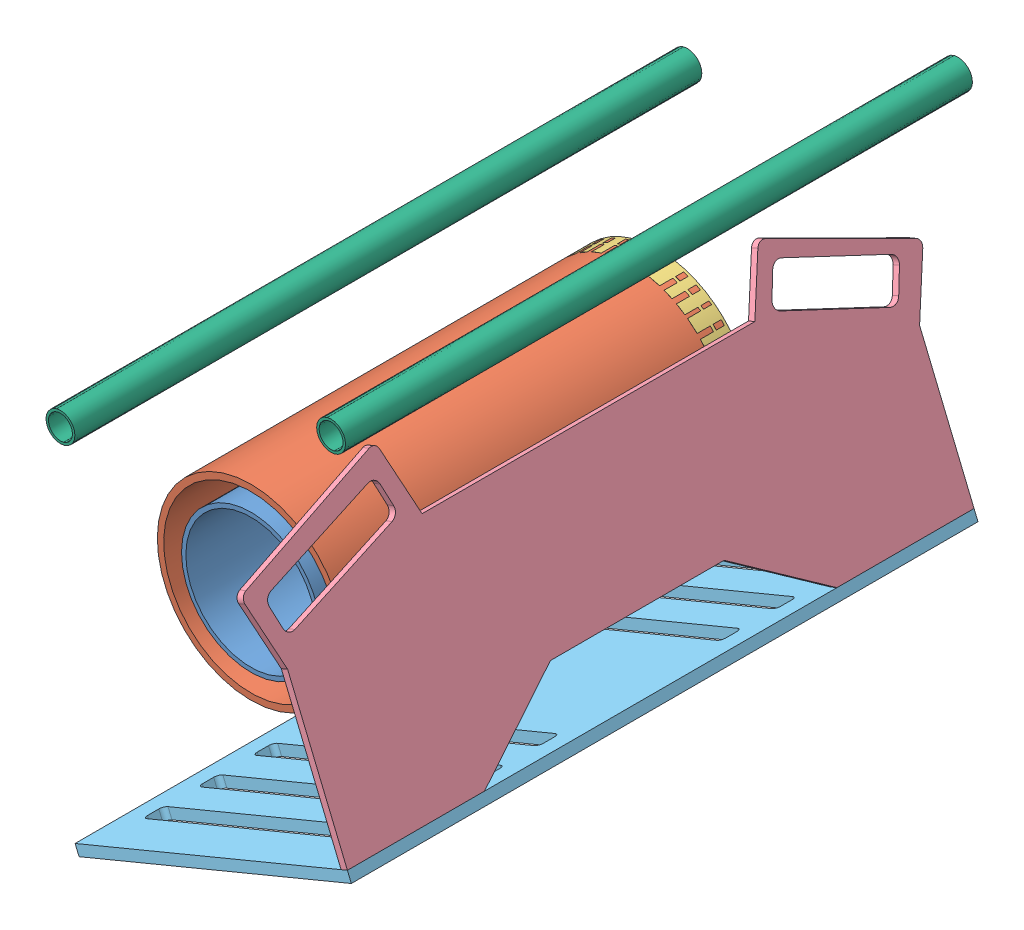
SolidWorks assembly Assem1, configuration Default. Lengths in mm.
Overall size (597.25 584.72 1095.77).
7 component instances, 6 part files, 11 mates.
Components (placement in the parent):
- inner_main_shell-1: inner_main_shell [Default] at (214.1698 315.1095 156.1721) size (202.6 202.6 590)
- outer_main_shell-1: outer_main_shell [Default] at (214.1698 315.1095 451.1721) x (0.580771 -0.814067 0) z (0 0 1) size (273.14 273.14 590)
- cap-1: cap [Default] at (214.1698 315.1095 155.0269) x (-0.923728 -0.383049 0) z (0 0 -1) size (273.04 273.04 38.74)
- side_frame-1: side_frame [Default] at (436.2247 330.1201 441.0447) x (0 0 -1) z (0.923728 0.383049 0) size (976.99 396.41 10)
- flat_frame-1: flat_frame [Default] at (313.8941 89.9427 441.0447) x (0 0 1) z (-0.923728 -0.383049 0) size (914 15 430)
- Pontoon-1: Pontoon [48925K94] at (-63.6755 384.8539 288.9721) size (42.16 42.16 914.4)
- Pontoon-2: Pontoon [48925K94] at (331.0443 571.2275 288.9721) size (42.16 42.16 914.4)
Mates (geometry in assembly coordinates):
- Concentric1: concentric anti-aligned: cylinder of inner_main_shell-1 through (214.1698 315.1095 746.1721) axis (0 0 -1) radius 95; cylinder of outer_main_shell-1 through (214.1698 315.1095 515.1017) axis (0 0 1) radius 127.3
- Coincident1: coincident aligned: plane of inner_main_shell-1 through (214.1698 315.1095 746.1721) normal (0 0 1); plane of outer_main_shell-1 through (325.3469 394.4254 746.1721) normal (0 0 1)
- Concentric2: concentric aligned: cylinder of inner_main_shell-1 through (214.1698 315.1095 746.1721) axis (0 0 -1) radius 95; cylinder of cap-1 through (214.1698 315.1095 101.1915) axis (0 0 -1) radius 95
- Coincident3: coincident anti-aligned: plane of outer_main_shell-1 through (325.3469 394.4254 156.1721) normal (0 0 -1); plane of cap-1 through (163.0251 438.4456 156.1721) normal (0 0 1)
- Parallel2: parallel aligned: plane of inner_main_shell-1 through (214.1698 315.1095 746.1721) normal (0 0 1); plane of side_frame-1 through (506.7499 186.1542 898.0447) normal (0 0 1)
- Parallel3: parallel anti-aligned: plane of side_frame-1 through (506.7499 186.1542 898.0447) normal (0 0 1); plane of flat_frame-1 through (151.6086 22.6466 829.3465) normal (0 0 -1)
- Coincident6: coincident anti-aligned: plane of side_frame-1 through (506.7499 186.1542 898.0447) normal (0.383049 -0.923728 0); plane of flat_frame-1 through (308.1483 103.7986 441.0447) normal (-0.383049 0.923728 0)
- Coincident7: coincident: plane of side_frame-1 through (506.7499 186.1542 898.0447) normal (0 0 1); line of flat_frame-1 through (109.5468 21.4431 898.0447) axis (0.923728 0.383049 0)
- Coincident8: coincident aligned: plane of side_frame-1 through (397.7759 448.9465 -39.4433) normal (0.923728 0.383049 0); plane of flat_frame-1 through (506.7499 186.1542 -15.9553) normal (0.923728 0.383049 0)
- Coincident9: coincident aligned: plane of Pontoon-1 through (-63.6755 384.8539 746.1721) normal (0 0 1); circle of Pontoon-2
- Coincident10: coincident aligned: plane of outer_main_shell-1 through (325.3469 394.4254 746.1721) normal (0 0 1); plane of Pontoon-1 through (-63.6755 384.8539 746.1721) normal (0 0 1)
